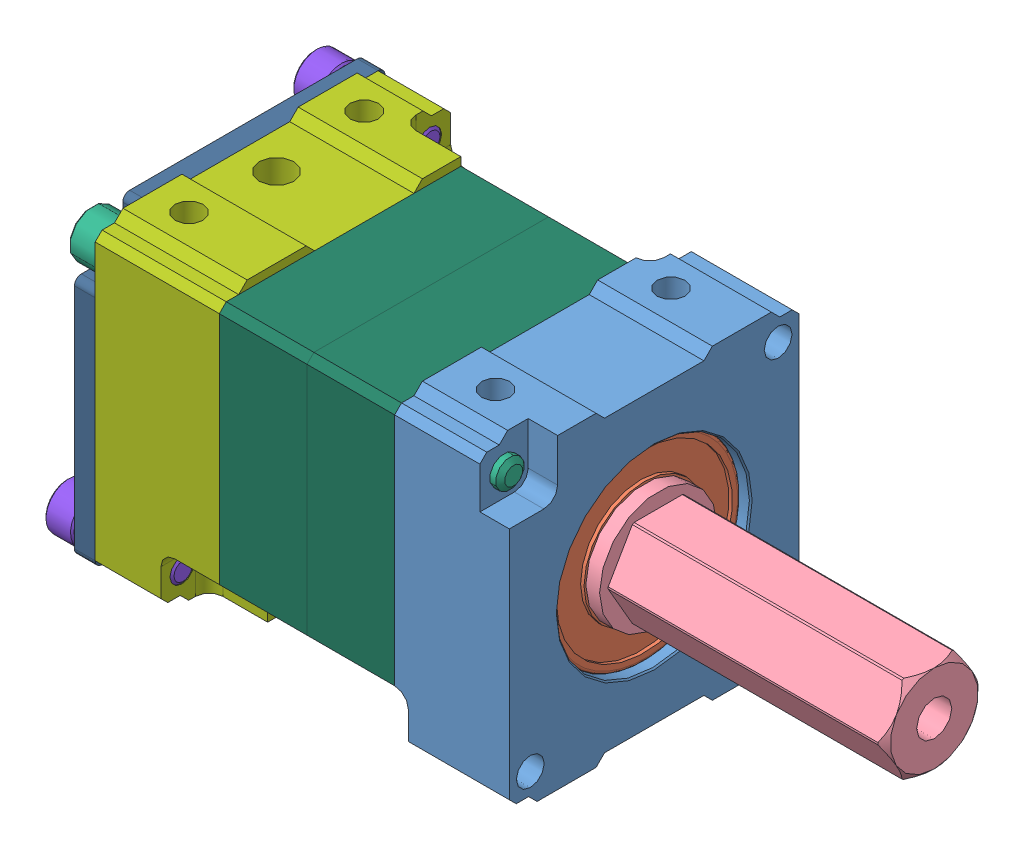
SolidWorks assembly VersaPlanetary_v2_Two_Stage_100_1_with_BAG, configuration Default. Lengths in mm.
Overall size (110.6 49.05 49.3).
39 component instances, 18 part files, 0 mates.
Components (placement in the parent):
- 217-2625-026 Rev1-1: 217-2625-026 Rev1 [Default] at (-6.5 22.225 0) x (0 -1 0) z (-1 0 0) size (44.45 42 18.13)
- 217-2742-001 Rev4-1: 217-2742-001 Rev4 [Default] at (0.2002 22.225 0) x (1 0 0) z (0 -0.092627 0.995701) size (7 28 28)
- 217-2742-001 Rev4-2: 217-2742-001 Rev4 [Default] at (8.2002 22.225 0) size (7 28 28)
- 217-2625-017 Rev1_9714K61-1: 217-2625-017 Rev1_9714K61 [Default] at (7.42 22.3002 -0.342) x (0 0.56703 0.823697) z (0 -0.823697 0.56703) size (28.51 4.98 30.18)
- 217-2625-003 Rev1-1: 217-2625-003 Rev1 [Default] at (7.4478 22.225 0) x (0 -1 0) z (1 0 0) size (17 17 64.12)
- 217-2625-018 Rev1_98541A410-1: 217-2625-018 Rev1_98541A410 [Default] at (-0.7046 22.225 0) x (1 0 0) z (0 -0.017452 0.999848) size (1 19.6 17.4)
- 832-2250-Base-Kit-Screw_SSA0832-0500ZC-1: 832-2250-Base-Kit-Screw_SSA0832-0500ZC [Default] at (-43.4 4.725 -17.5) x (0 -0.767799 -0.640691) z (0 0.640691 -0.767799) size (6.73 61.21 6.73)
- 832-2250-Base-Kit-Screw_SSA0832-0500ZC-2: 832-2250-Base-Kit-Screw_SSA0832-0500ZC [Default] at (-43.4 39.725 17.5) x (0 0.961307 0.275478) z (0 -0.275478 0.961307) size (6.73 61.21 6.73)
- 217-2625-025 Rev1-1: 217-2625-025 Rev1 [Default] at (-35.9 22.225 0) x (0 -1 0) z (-1 0 0) size (44.45 42 18)
- 217-4649-002 Rev1_SSA0832-0500ZC-1: 217-4649-002 Rev1_SSA0832-0500ZC [Default] at (-46.4 4.2645 17.9605) x (0 0.33842 -0.940995) z (0 0.940995 0.33842) size (6.73 16.76 6.73)
- 217-4649-002 Rev1_SSA0832-0500ZC-2: 217-4649-002 Rev1_SSA0832-0500ZC [Default] at (-46.4 40.1855 -17.9605) x (0 -0.308932 -0.951084) z (0 0.951084 -0.308932) size (6.73 16.76 6.73)
- 217-4649-006 Rev1_SSA0004-008BA-1: 217-4649-006 Rev1_SSA0004-008BA [Default] at (-43.4 22.225 12.5) x (0 0.5 -0.866025) z (0 -0.866025 -0.5) size (7 14 7)
- 217-4649-006 Rev1_SSA0004-008BA-2: 217-4649-006 Rev1_SSA0004-008BA [Default] at (-43.4 22.225 -12.5) x (0 -0.5 0.866025) z (0 0.866025 0.5) size (7 14 7)
- 217-2822-003 Rev4-1: 217-2822-003 Rev4 [Default] at (-44.9 22.225 0) x (0 -1 0) z (-1 0 0) size (42 42 4.8)
- 217-2820 Rev1_Public-1: 217-2820 Rev1_Public [Default] at (-4.6546 22.225 0) x (0 -0.456494 0.889726) z (-1 0 0) size (39.26 38.9 17.4)
  - 217-2625-100-1: 217-2625-100 [Default] at origin size (39.26 38.9 12.7)
    - 217-2625-008 Rev1-1: 217-2625-008 Rev1 [Default] at origin size (34.7 34.7 4.7)
    - 217-2625-010 Rev1-1: 217-2625-010 Rev1 [Default] at (0 10.193 3.65) x (0.999813 0.019336 0) z (0 0 1) size (4 4 12)
    - 217-2625-010 Rev1-2: 217-2625-010 Rev1 [Default] at (8.691 -5.3258 3.65) size (4 4 12)
    - 217-2625-010 Rev1-3: 217-2625-010 Rev1 [Default] at (-8.691 -5.3258 3.65) size (4 4 12)
    - 217-2625-005 Rev1_Planet_Revolving_Follower01-1: 217-2625-005 Rev1_Planet_Revolving_Follower01 [Default] at (8.691 -5.3258 6.35) x (0.932816 0.360354 0) z (0 0 1) size (16.91 16.92 8)
    - 217-2625-005 Rev1_Planet_Revolving_Follower01-2: 217-2625-005 Rev1_Planet_Revolving_Follower01 [Default] at (-8.691 -5.3258 6.35) x (-0.932788 -0.360426 0) z (0 0 1) size (16.91 16.92 8)
    - 217-2625-005 Rev1_Planet_Revolving_Follower01-3: 217-2625-005 Rev1_Planet_Revolving_Follower01 [Default] at (0 10.193 6.35) x (0.893583 0.448898 0) z (0 0 1) size (16.91 16.92 8)
  - 217-2625-007 Rev1_Public-1: 217-2625-007 Rev1_Public [Default] at (0 0 6.7) x (0.992772 0.120019 0) z (0 0 1) size (14.49 14.49 12.72)
- 217-2816-001 Rev1-1: 217-2816-001 Rev1 [Default] at (-6.35 22.225 0) x (0 -1 0) z (1 0 0) size (42 42 14.5)
- 217-2820 Rev1_Public-2: 217-2820 Rev1_Public [Default] at (-17.15 22.225 0) x (0 0.184082 0.982911) z (-1 0 0) size (39.26 38.9 17.4)
  - 217-2625-100-1: 217-2625-100 [Default] at origin size (39.26 38.9 12.7)
    - 217-2625-008 Rev1-1: 217-2625-008 Rev1 [Default] at origin size (34.7 34.7 4.7)
    - 217-2625-010 Rev1-1: 217-2625-010 Rev1 [Default] at (0 10.193 3.65) x (0.999813 0.019336 0) z (0 0 1) size (4 4 12)
    - 217-2625-010 Rev1-2: 217-2625-010 Rev1 [Default] at (8.691 -5.3258 3.65) size (4 4 12)
    - 217-2625-010 Rev1-3: 217-2625-010 Rev1 [Default] at (-8.691 -5.3258 3.65) size (4 4 12)
    - 217-2625-005 Rev1_Planet_Revolving_Follower01-1: 217-2625-005 Rev1_Planet_Revolving_Follower01 [Default] at (8.691 -5.3258 6.35) x (0.932816 0.360354 0) z (0 0 1) size (16.91 16.92 8)
    - 217-2625-005 Rev1_Planet_Revolving_Follower01-2: 217-2625-005 Rev1_Planet_Revolving_Follower01 [Default] at (-8.691 -5.3258 6.35) x (-0.932788 -0.360426 0) z (0 0 1) size (16.91 16.92 8)
    - 217-2625-005 Rev1_Planet_Revolving_Follower01-3: 217-2625-005 Rev1_Planet_Revolving_Follower01 [Default] at (0 10.193 6.35) x (0.893583 0.448898 0) z (0 0 1) size (16.91 16.92 8)
  - 217-2625-007 Rev1_Public-1: 217-2625-007 Rev1_Public [Default] at (0 0 6.7) x (0.992772 0.120019 0) z (0 0 1) size (14.49 14.49 12.72)
- 217-2816-001 Rev1-2: 217-2816-001 Rev1 [Default] at (-19.05 22.225 0) x (0 -1 0) z (1 0 0) size (42 42 14.5)
- 217-4649-001 Rev1-1: 217-4649-001 Rev1 [Default] at (-32.746 22.225 0) x (0 -1 0) z (1 0 0) size (18 18 13)
- 217-4649-007 Rev1_94105A824-1: 217-4649-007 Rev1_94105A824 [Default] at (-38.221 22.225 -6.7835) x (-0.996104 -0.088191 0) z (0 0 -1) size (4.83 4.83 4.9)
- 217-2625-011 Rev1-1: 217-2625-011 Rev1 [Default] at (-37.4818 22.225 0) x (0 0 1) z (0 -1 0) size (8.01 7.5 7.94)
